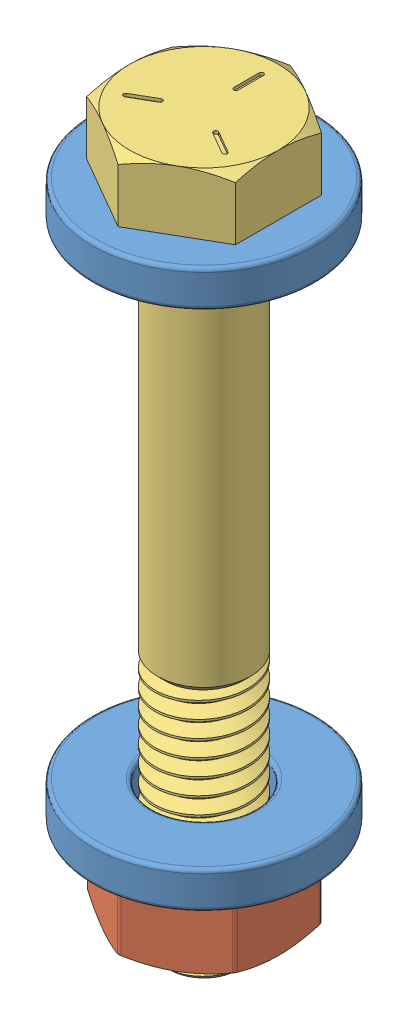
SolidWorks assembly t_slot_railplate_screw_assembly, configuration Default. Lengths in mm.
Overall size (26.37 62.83 26.37).
4 component instances, 3 part files, 11 mates.
Components (placement in the parent):
- 5-16x.75 oversize washer 91525A326_316 Stainless Steel Washer-3: 5-16x.75 oversize washer 91525A326_316 Stainless Steel Washer [91525A326] at (0 1.5875 0) x (0.837169 0 0.546944) z (0 1 0) size (19.05 19.05 3.17)
- 5-16x.75 oversize washer 91525A326_316 Stainless Steel Washer-4: 5-16x.75 oversize washer 91525A326_316 Stainless Steel Washer [91525A326] at (0 -42.8625 0) x (1 0 0) z (0 -1 0) size (19.05 19.05 3.17)
- 5-18 nut 95462A030_Medium-Strength Steel Hex Nut(1)-1: 5-18 nut 95462A030_Medium-Strength Steel Hex Nut(1) [95462A030] at (0 -47.8234 0) x (1 0 0) z (0 1 0) size (12.7 14.57 7.61)
- 5s16p18x2.25in bolt 91247A592_Medium-Strength Grade 5 Steel Hex Head Screw-1: 5s16p18x2.25in bolt 91247A592_Medium-Strength Grade 5 Steel Hex Head Screw [91247A592] at (0 -22.8203 0) x (0 -1 0) z (-0.5 0 0.866025) size (62.83 14.66 12.7)
Mates (geometry in assembly coordinates):
- Concentric1: concentric aligned: cylinder of 5-16x.75 oversize washer 91525A326_316 Stainless Steel Washer-3 through (0 0 0) axis (0 1 0) radius 4.3688
- Coincident8: coincident anti-aligned: plane of 5-16x.75 oversize washer 91525A326_316 Stainless Steel Washer-3 through (0 0 0) normal (0 -1 0)
- Concentric2: concentric anti-aligned: cylinder of 5-16x.75 oversize washer 91525A326_316 Stainless Steel Washer-3 through (0 0 0) axis (0 1 0) radius 4.3688; cylinder of 5-16x.75 oversize washer 91525A326_316 Stainless Steel Washer-4 through (0 -41.275 0) axis (0 -1 0) radius 4.3688
- Distance1: distance = 41.275 mm anti-aligned: plane of 5-16x.75 oversize washer 91525A326_316 Stainless Steel Washer-4 through (0 -41.275 0) normal (0 1 0); plane of 5-16x.75 oversize washer 91525A326_316 Stainless Steel Washer-3 through (0 0 0) normal (0 -1 0)
- Coincident12: coincident anti-aligned: plane of 5-16x.75 oversize washer 91525A326_316 Stainless Steel Washer-4 through (0 -44.45 0) normal (0 -1 0); plane of 5-18 nut 95462A030_Medium-Strength Steel Hex Nut(1)-1 through (0 -44.45 0) normal (0 1 0)
- Concentric4: concentric anti-aligned: circle of 5-16x.75 oversize washer 91525A326_316 Stainless Steel Washer-4; circle of 5-18 nut 95462A030_Medium-Strength Steel Hex Nut(1)-1
- Concentric6: concentric anti-aligned: cylinder of 5-16x.75 oversize washer 91525A326_316 Stainless Steel Washer-3 through (0 0 0) axis (0 1 0) radius 4.3688; cylinder of 5s16p18x2.25in bolt 91247A592_Medium-Strength Grade 5 Steel Hex Head Screw-1 through (0 3.175 0) axis (0 -1 0) radius 3.9688
- Coincident14: coincident anti-aligned: plane of 5-16x.75 oversize washer 91525A326_316 Stainless Steel Washer-3 through (0 3.175 0) normal (0 1 0); plane of 5s16p18x2.25in bolt 91247A592_Medium-Strength Grade 5 Steel Hex Head Screw-1 through (0 3.175 7.3323) normal (0 -1 0)
- Coincident15: coincident aligned: plane of 5-18 nut 95462A030_Medium-Strength Steel Hex Nut(1)-1 through (-6.35 -44.45 -3.6662) normal (-1 0 0); plane of 5s16p18x2.25in bolt 91247A592_Medium-Strength Grade 5 Steel Hex Head Screw-1 through (-6.35 8.3344 -3.6662) normal (-1 0 0)
- Coincident16: coincident aligned: plane of 5-18 nut 95462A030_Medium-Strength Steel Hex Nut(1)-1 through (0 -47.8234 0) normal (1 0 0)
- Coincident17: coincident aligned: plane of 5-16x.75 oversize washer 91525A326_316 Stainless Steel Washer-4 through (0 -42.8625 0) normal (1 0 0)
